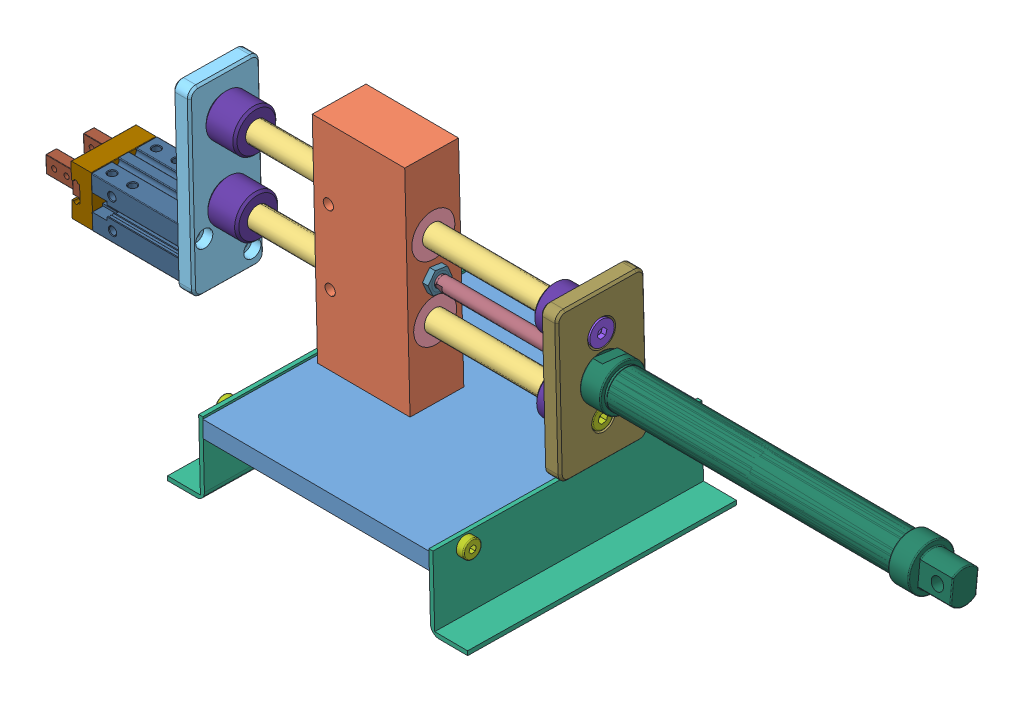
SolidWorks assembly cum s3, configuration Default. Lengths in mm.
Overall size (436.68 137.7 128.52).
36 component instances, 17 part files, 73 mates.
Components (placement in the parent):
- tam de lon-1: tam de lon [Default] at (119.0958 51.1975 54.0073) x (-0.999587 -0.017639 -0.022689) z (-0.022562 -0.007384 0.999718) size (110 8 125)
- con truot s1-2: con truot s1 [Default] at (88.5768 136.6703 53.9498) x (0.999587 0.017639 0.022689) z (0.022562 0.007384 -0.999718) size (45 102 25)
- chot dan huong-1: chot dan huong [Default] at (10.2966 117.7866 52.0436) x (0.021471 -0.983136 -0.181614) z (-0.019103 -0.182026 0.983108) size (10 175 10)
- chot dan huong-2: chot dan huong [Default] at (10.9197 82.793 51.7993) x (0.026236 -0.237789 -0.970963) z (0.011731 -0.971157 0.238153) size (10 175 10)
- bac lot-1: bac lot [Default] at (66.3976 118.7766 53.3171) x (0.028076 -0.767933 -0.639915) z (-0.006137 -0.640287 0.768111) size (20 12 20)
- bac lot-2: bac lot [Default] at (67.0207 83.783 53.0727) x (0.018145 -0.999587 -0.022287) z (-0.022287 -0.022689 0.999494) size (20 12 20)
- bac lot-3: bac lot [Default] at (111.379 119.5704 54.3381) x (-0.014484 -0.372719 0.927831) z (0.024823 -0.927776 -0.37231) size (20 12 20)
- bac lot-4: bac lot [Default] at (112.0021 84.5768 54.0937) x (-0.014484 -0.372719 0.927831) z (0.024823 -0.927776 -0.37231) size (20 12 20)
- ban canh truoc-1: ban canh truoc [Default] at (10.7506 92.2913 51.8656) x (-0.022562 -0.007384 0.999718) z (0.017801 -0.999817 -0.006983) size (33 8 86)
- khoi do-1: khoi do [Default] at (173.7917 36.5109 117.6508) x (0.022562 0.007384 -0.999718) z (-0.999587 -0.017639 -0.022689) size (125 35 18)
- khoi do-2: khoi do [Default] at (64.9414 35.4633 -9.8487) x (-0.022562 -0.007384 0.999718) z (0.999587 0.017639 0.022689) size (125 35 18)
- socket head thin cap screw_din-2: socket head thin cap screw_din [DIN 7984 - M5 x 12 --- 9.6N] at (57.6203 45.7804 100.0932) x (0.999587 0.017639 0.022689) z (-0.022689 -0.0002 0.999743) size (15.5 8.5 8.5)
- socket head thin cap screw_din-3: socket head thin cap screw_din [DIN 7984 - M5 x 12 --- 9.6N] at (59.7637 46.4818 5.12) x (0.999587 0.017639 0.022689) z (-0.022689 -0.0002 0.999743) size (15.5 8.5 8.5)
- socket head thin cap screw_din-4: socket head thin cap screw_din [DIN 7984 - M5 x 12 --- 9.6N] at (180.7137 48.6161 7.8654) x (-0.999587 -0.017639 -0.022689) z (0.022689 -0.968916 -0.246346) size (15.5 8.5 8.5)
- socket head thin cap screw_din-5: socket head thin cap screw_din [DIN 7984 - M5 x 12 --- 9.6N] at (178.5703 47.9147 102.8386) x (-0.999587 -0.017639 -0.022689) z (0.022689 -0.968916 -0.246346) size (15.5 8.5 8.5)
- socket head thin cap screw_din-6: socket head thin cap screw_din [DIN 7984 - M5 x 12 --- 9.6N] at (108.0343 45.1492 61.2151) x (-0.017801 0.999817 0.006983) z (-0.006983 -0.007108 0.99995) size (15.5 8.5 8.5)
- socket head thin cap screw_din-7: socket head thin cap screw_din [DIN 7984 - M5 x 12 --- 9.6N] at (72.3876 44.6249 45.4025) x (-0.017801 0.999817 0.006983) z (-0.006983 -0.007108 0.99995) size (15.5 8.5 8.5)
- socket head thin cap screw_din-10: socket head thin cap screw_din [DIN 7984 - M6 x 14 --- 11N] at (3.1229 82.6555 51.6223) x (0.999587 0.017639 0.022689) z (-0.022689 -0.0002 0.999743) size (18 10 10)
- socket csink head cap screw 10642_din-2: socket csink head cap screw 10642_din [EN ISO 10642 - M6 x 16 - 16N] at (2.08 117.6417 51.8571) x (0.999587 0.017639 0.022689) z (-0.022678 -0.000819 0.999742) size (16 11.34 11.34)
- NMHZ2-16D-1: NMHZ2-16D [Default] at (18.7852 62.0278 29.4102) x (-0.022562 -0.007384 0.999718) z (-0.999587 -0.017639 -0.022689) size (30.6 23.6 52.5)
  - NMHZ2-16D Slipway-1: NMHZ2-16D Slipway [Default] at (22.4069 2.6078 57.488) size (30.1 23.6 10)
  - NMHZ2-16D cylinder-2: NMHZ2-16D cylinder [Default] at (22.4069 2.6078 14.988) size (30.6 23.6 42.5)
- NMHZ2-16D air claw-1: NMHZ2-16D air claw [Default] at (-47.2443 63.3091 51.0796) x (-0.022562 -0.007384 0.999718) z (-0.999587 -0.017639 -0.022689) size (12 10 21)
- NMHZ2-16D air claw-2: NMHZ2-16D air claw [Default] at (-47.1889 63.3273 48.6222) x (0.022562 0.007384 -0.999718) z (-0.999587 -0.017639 -0.022689) size (12 10 21)
- ban canh sau-1: ban canh sau [Default] at (185.5359 103.3766 55.8921) x (-0.022562 -0.007384 0.999718) z (-0.017801 0.999817 0.006983) size (41 8 70)
- socket head thin cap screw_din-11: socket head thin cap screw_din [DIN 7984 - M6 x 14 --- 11N] at (193.6442 86.0174 55.9469) x (-0.999587 -0.017639 -0.022689) z (0.022689 -0.968916 -0.246346) size (18 10 10)
- socket csink head cap screw 10642_din-6: socket csink head cap screw 10642_din [EN ISO 10642 - M6 x 16 - 16N] at (193.441 121.0184 56.2008) x (-0.999587 -0.017639 -0.022689) z (0.022777 -0.96767 -0.251187) size (16 11.34 11.34)
- Part1-1: Part1 [Default] at (260.6534 104.7022 57.5972) x (-0.014484 -0.372719 0.927831) z (0.024823 -0.927776 -0.37231) size (6.2 165 6.2)
- Part2-1: Part2 [Default] at (113.19 102.1 54.2499) x (0.000299 -0.795842 0.605505) z (0.028738 -0.605248 -0.795518) size (11.32 3 9.8)
- Assem2-1: Assem2 [Default] at (390.8157 29.8557 191.0632) x (0.024605 -0.1173 -0.992792) z (0.999587 0.017639 0.022689) size (21.5 21.5 192)
  - 16 X 100 Cylinder bore-1: 16 X 100 Cylinder bore [Default] at (120.5218 91.9581 -118.7652) size (21.5 21.5 192)
- prevailing torque nut style 2 fine_din-3: prevailing torque nut style 2 fine_din [DIN EN ISO 10513 - M10x1 - N] at (175.54 103.2002 55.6652) x (-0.025491 0.908776 0.416506) z (-0.999587 -0.017639 -0.022689) size (17.25 18.48 10)
- bac chan-1: bac chan [Default] at (10.2966 117.7866 52.0436) x (0.014063 0.388293 -0.921429) z (0.025063 -0.921367 -0.387885) size (20 15 20)
- bac chan-2: bac chan [Default] at (10.9197 82.793 51.7993) x (0.014063 0.388293 -0.921429) z (0.025063 -0.921367 -0.387885) size (20 15 20)
- bac chan-3: bac chan [Default] at (170.2305 120.6089 55.6739) x (0.016197 -0.997929 0.062249) z (-0.02374 0.061856 0.997803) size (20 15 20)
- bac chan-4: bac chan [Default] at (170.8536 85.6153 55.4295) x (0.016861 -0.999279 0.034017) z (-0.023273 0.03362 0.999164) size (20 15 20)
Mates (geometry in assembly coordinates):
- Parallel5: parallel anti-aligned: plane of tam de lon-1 through (119.0958 51.1975 54.0073) normal (-0.017801 0.999817 0.006983); plane of con truot s1-2 through (90.1077 50.686 53.3493) normal (0.017801 -0.999817 -0.006983)
- Parallel6: parallel anti-aligned: plane of tam de lon-1 through (172.8053 43.7076 117.6817) normal (-0.022562 -0.007384 0.999718); plane of con truot s1-2 through (67.6142 66.3785 40.454) normal (0.022562 0.007384 -0.999718)
- Concentric3: concentric aligned: cylinder of tam de lon-1 through (72.2844 50.4239 45.443) axis (0.017801 -0.999817 -0.006983) radius 2.75; circle of con truot s1-2
- Coincident1: coincident anti-aligned: plane of tam de lon-1 through (119.0958 51.1975 54.0073) normal (-0.017801 0.999817 0.006983); plane of con truot s1-2 through (90.1077 50.686 53.3493) normal (0.017801 -0.999817 -0.006983)
- Concentric4: concentric anti-aligned: cylinder of con truot s1-2 through (41.408 118.3356 52.7498) axis (0.999587 0.017639 0.022689) radius 6; cylinder of chot dan huong-1 through (283.1839 122.602 58.2378) axis (-0.999587 -0.017639 -0.022689) radius 5
- Concentric5: concentric anti-aligned: cylinder of con truot s1-2 through (42.031 83.342 52.5054) axis (0.999587 0.017639 0.022689) radius 6; cylinder of chot dan huong-2 through (283.8069 87.6084 57.9934) axis (-0.999587 -0.017639 -0.022689) radius 5
- Concentric6: concentric anti-aligned: cylinder of con truot s1-2 through (41.408 118.3356 52.7498) axis (0.999587 0.017639 0.022689) radius 6; cylinder of bac lot-1 through (78.3927 118.9883 53.5893) axis (-0.999587 -0.017639 -0.022689) radius 6
- Coincident2: coincident anti-aligned: plane of con truot s1-2 through (68.3968 118.8119 53.3624) normal (-0.999587 -0.017639 -0.022689); plane of bac lot-1 through (68.3968 118.8119 53.3624) normal (0.999587 0.017639 0.022689)
- Concentric7: concentric anti-aligned: cylinder of con truot s1-2 through (42.031 83.342 52.5054) axis (0.999587 0.017639 0.022689) radius 6; cylinder of bac lot-2 through (79.0157 83.9947 53.3449) axis (-0.999587 -0.017639 -0.022689) radius 6
- Coincident3: coincident anti-aligned: plane of con truot s1-2 through (69.0199 83.8183 53.1181) normal (-0.999587 -0.017639 -0.022689); plane of bac lot-2 through (69.0199 83.8183 53.1181) normal (0.999587 0.017639 0.022689)
- Concentric8: concentric aligned: cylinder of con truot s1-2 through (41.408 118.3356 52.7498) axis (0.999587 0.017639 0.022689) radius 6; cylinder of bac lot-3 through (99.384 119.3587 54.0658) axis (0.999587 0.017639 0.022689) radius 6
- Coincident4: coincident anti-aligned: plane of con truot s1-2 through (109.3799 119.5351 54.2927) normal (0.999587 0.017639 0.022689); plane of bac lot-3 through (109.3799 119.5351 54.2927) normal (-0.999587 -0.017639 -0.022689)
- Concentric9: concentric aligned: cylinder of con truot s1-2 through (42.031 83.342 52.5054) axis (0.999587 0.017639 0.022689) radius 6; cylinder of bac lot-4 through (100.0071 84.3651 53.8214) axis (0.999587 0.017639 0.022689) radius 6
- Coincident5: coincident anti-aligned: plane of con truot s1-2 through (110.0029 84.5415 54.0483) normal (0.999587 0.017639 0.022689); plane of bac lot-4 through (110.0029 84.5415 54.0483) normal (-0.999587 -0.017639 -0.022689)
- Concentric10: concentric aligned: cylinder of chot dan huong-1 through (283.1839 122.602 58.2378) axis (-0.999587 -0.017639 -0.022689) radius 5; cylinder of ban canh truoc-1 through (10.2966 117.7866 52.0436) axis (-0.999587 -0.017639 -0.022689) radius 3.3
- Concentric11: concentric aligned: cylinder of chot dan huong-2 through (283.8069 87.6084 57.9934) axis (-0.999587 -0.017639 -0.022689) radius 5; cylinder of ban canh truoc-1 through (10.9197 82.793 51.7993) axis (-0.999587 -0.017639 -0.022689) radius 3.3
- Coincident6: coincident anti-aligned: plane of chot dan huong-1 through (10.2966 117.7866 52.0436) normal (-0.999587 -0.017639 -0.022689); plane of ban canh truoc-1 through (10.7506 92.2913 51.8656) normal (0.999587 0.017639 0.022689)
- Coincident7: coincident anti-aligned: plane of chot dan huong-2 through (10.9197 82.793 51.7993) normal (-0.999587 -0.017639 -0.022689); plane of ban canh truoc-1 through (10.7506 92.2913 51.8656) normal (0.999587 0.017639 0.022689)
- Parallel7: parallel aligned: plane of tam de lon-1 through (65.671 42.6903 -9.7789) normal (-0.999587 -0.017639 -0.022689); plane of khoi do-1 through (176.0884 18.6354 -7.4646) normal (-0.999587 -0.017639 -0.022689)
- Parallel8: parallel aligned: plane of tam de lon-1 through (119.0958 51.1975 54.0073) normal (-0.017801 0.999817 0.006983); plane of khoi do-1 through (175.4654 53.629 -7.2202) normal (-0.017801 0.999817 0.006983)
- Concentric14: concentric aligned: cylinder of tam de lon-1 through (160.2221 48.2545 7.4003) axis (0.999587 0.017639 0.022689) radius 2.5; cylinder of khoi do-1 through (52.2667 46.3495 4.9498) axis (0.999587 0.017639 0.022689) radius 2.5
- Coincident10: coincident anti-aligned: plane of tam de lon-1 through (175.6256 44.6306 -7.2831) normal (0.999587 0.017639 0.022689); plane of khoi do-1 through (176.0884 18.6354 -7.4646) normal (-0.999587 -0.017639 -0.022689)
- Parallel9: parallel anti-aligned: plane of tam de lon-1 through (65.671 42.6903 -9.7789) normal (-0.999587 -0.017639 -0.022689); plane of khoi do-2 through (63.3136 15.7721 115.0043) normal (0.999587 0.017639 0.022689)
- Parallel10: parallel anti-aligned: plane of tam de lon-1 through (119.0958 51.1975 54.0073) normal (-0.017801 0.999817 0.006983); plane of khoi do-2 through (63.3136 15.7721 115.0043) normal (0.017801 -0.999817 -0.006983)
- Concentric15: concentric aligned: cylinder of tam de lon-1 through (80.2552 46.8434 5.5851) axis (-0.999587 -0.017639 -0.022689) radius 2.5; cylinder of khoi do-2 through (188.2106 48.7484 8.0356) axis (-0.999587 -0.017639 -0.022689) radius 2.5
- Coincident11: coincident anti-aligned: plane of tam de lon-1 through (65.671 42.6903 -9.7789) normal (-0.999587 -0.017639 -0.022689); plane of khoi do-2 through (63.3136 15.7721 115.0043) normal (0.999587 0.017639 0.022689)
- Concentric16: concentric aligned: cylinder of khoi do-2 through (186.0672 48.047 103.0088) axis (-0.999587 -0.017639 -0.022689) radius 2.5; cylinder of socket head thin cap screw_din-2 through (25.8834 45.2204 99.3728) axis (-0.999587 -0.017639 -0.022689) radius 4.25
- Coincident12: coincident anti-aligned: plane of khoi do-2 through (61.2788 17.7365 114.9729) normal (-0.999587 -0.017639 -0.022689); plane of socket head thin cap screw_din-2 through (61.0438 50.0915 100.1718) normal (0.999587 0.017639 0.022689)
- Concentric17: concentric aligned: cylinder of khoi do-2 through (188.2106 48.7484 8.0356) axis (-0.999587 -0.017639 -0.022689) radius 2.5; cylinder of socket head thin cap screw_din-3 through (28.0268 45.9218 4.3996) axis (-0.999587 -0.017639 -0.022689) radius 4.25
- Coincident13: coincident anti-aligned: plane of khoi do-2 through (61.2788 17.7365 114.9729) normal (-0.999587 -0.017639 -0.022689); plane of socket head thin cap screw_din-3 through (63.1872 50.7929 5.1986) normal (0.999587 0.017639 0.022689)
- Concentric18: concentric aligned: cylinder of khoi do-1 through (52.2667 46.3495 4.9498) axis (0.999587 0.017639 0.022689) radius 2.5; cylinder of socket head thin cap screw_din-4 through (212.4506 49.1762 8.5858) axis (0.999587 0.017639 0.022689) radius 4.25
- Coincident14: coincident anti-aligned: plane of khoi do-1 through (178.052 20.6703 -7.4053) normal (0.999587 0.017639 0.022689); plane of socket head thin cap screw_din-4 through (177.2901 49.6031 3.6681) normal (-0.999587 -0.017639 -0.022689)
- Concentric19: concentric aligned: cylinder of khoi do-1 through (50.1234 45.6481 99.9231) axis (0.999587 0.017639 0.022689) radius 2.5; cylinder of socket head thin cap screw_din-5 through (210.3072 48.4747 103.559) axis (0.999587 0.017639 0.022689) radius 4.25
- Coincident15: coincident anti-aligned: plane of khoi do-1 through (178.052 20.6703 -7.4053) normal (0.999587 0.017639 0.022689); plane of socket head thin cap screw_din-5 through (175.1467 48.9017 98.6413) normal (-0.999587 -0.017639 -0.022689)
- Concentric20: concentric aligned: cylinder of tam de lon-1 through (107.972 48.6485 61.2395) axis (0.017801 -0.999817 -0.006983) radius 5; cylinder of socket head thin cap screw_din-6 through (108.5995 13.405 60.9934) axis (0.017801 -0.999817 -0.006983) radius 4.25
- Coincident16: coincident anti-aligned: plane of tam de lon-1 through (107.972 48.6485 61.2395) normal (0.017801 -0.999817 -0.006983); plane of socket head thin cap screw_din-6 through (103.7228 48.5731 61.2093) normal (-0.017801 0.999817 0.006983)
- Concentric21: concentric aligned: cylinder of tam de lon-1 through (72.2844 50.4239 45.443) axis (0.017801 -0.999817 -0.006983) radius 2.75; cylinder of socket head thin cap screw_din-7 through (72.9528 12.8807 45.1808) axis (0.017801 -0.999817 -0.006983) radius 4.25
- Coincident17: coincident anti-aligned: plane of tam de lon-1 through (72.3253 48.1243 45.4269) normal (0.017801 -0.999817 -0.006983); plane of socket head thin cap screw_din-7 through (68.0761 48.0489 45.3967) normal (-0.017801 0.999817 0.006983)
- Concentric23: concentric aligned: cylinder of ban canh truoc-1 through (7.1212 82.726 51.713) axis (-0.999587 -0.017639 -0.022689) radius 5.5; cylinder of socket head thin cap screw_din-10 through (-28.614 82.0954 50.9019) axis (-0.999587 -0.017639 -0.022689) radius 5
- Coincident19: coincident anti-aligned: plane of ban canh truoc-1 through (7.1212 82.726 51.713) normal (-0.999587 -0.017639 -0.022689); plane of socket head thin cap screw_din-10 through (7.0331 87.7252 51.712) normal (0.999587 0.017639 0.022689)
- Coincident20: coincident aligned: cone of ban canh truoc-1 through (5.4986 117.702 51.9347) axis (0.999587 0.017639 0.022689); cone of socket csink head cap screw 10642_din-2 through (3.1296 117.6602 51.881) axis (0.999587 0.017639 0.022689)
- Concentric24: concentric anti-aligned: cylinder of ban canh truoc-1 through (10.8638 71.9138 62.7207) axis (-0.999587 -0.017639 -0.022689) radius 2.25; cylinder of NMHZ2-16D-1/NMHZ2-16D cylinder-2 through (-12.1267 71.5081 62.1989) axis (0.999587 0.017639 0.022689) radius 2
- Concentric25: concentric aligned: cylinder of ban canh truoc-1 through (7.229 57.0014 40.5224) axis (0.999587 0.017639 0.022689) radius 4; cylinder of NMHZ2-16D-1/NMHZ2-16D cylinder-2 through (-11.3634 56.6733 40.1003) axis (0.999587 0.017639 0.022689) radius 2
- Coincident22: coincident anti-aligned: plane of ban canh truoc-1 through (2.7539 92.1502 51.6841) normal (-0.999587 -0.017639 -0.022689); plane of NMHZ2-16D-1/NMHZ2-16D cylinder-2 through (3.2514 64.2053 51.4889) normal (0.999587 0.017639 0.022689)
- Parallel11: parallel anti-aligned: plane of NMHZ2-16D-1/NMHZ2-16D Slipway-1 through (-44.7209 63.516 27.8948) normal (-0.999587 -0.017639 -0.022689); plane of NMHZ2-16D air claw-1 through (-45.5159 63.2558 63.1216) normal (0.999587 0.017639 0.022689)
- Concentric26: concentric anti-aligned: cylinder of NMHZ2-16D-1/NMHZ2-16D Slipway-1 through (-46.7913 67.4799 27.8774) axis (-0.022562 -0.007384 0.999718) radius 1; cylinder of NMHZ2-16D air claw-1 through (-47.5863 67.2198 63.1042) axis (0.022562 0.007384 -0.999718) radius 1
- Parallel12: parallel anti-aligned: plane of NMHZ2-16D-1/NMHZ2-16D Slipway-1 through (-44.7209 63.516 27.8948) normal (-0.999587 -0.017639 -0.022689); plane of NMHZ2-16D air claw-2 through (-44.919 63.4511 36.671) normal (0.999587 0.017639 0.022689)
- Concentric27: concentric aligned: cylinder of NMHZ2-16D-1/NMHZ2-16D Slipway-1 through (-46.6489 59.4814 27.8215) axis (-0.022562 -0.007384 0.999718) radius 1; cylinder of NMHZ2-16D air claw-2 through (-46.8469 59.4166 36.5977) axis (-0.022562 -0.007384 0.999718) radius 1
- Concentric28: concentric anti-aligned: cylinder of chot dan huong-1 through (283.1839 122.602 58.2378) axis (-0.999587 -0.017639 -0.022689) radius 5; cylinder of ban canh sau-1 through (185.2243 120.8734 56.0143) axis (0.999587 0.017639 0.022689) radius 3.3
- Concentric29: concentric anti-aligned: cylinder of chot dan huong-2 through (283.8069 87.6084 57.9934) axis (-0.999587 -0.017639 -0.022689) radius 5; cylinder of ban canh sau-1 through (185.8474 85.8798 55.7699) axis (0.999587 0.017639 0.022689) radius 3.3
- Coincident23: coincident anti-aligned: plane of chot dan huong-1 through (185.2243 120.8734 56.0143) normal (0.999587 0.017639 0.022689); plane of ban canh sau-1 through (185.5359 103.3766 55.8921) normal (-0.999587 -0.017639 -0.022689)
- Coincident24: coincident anti-aligned: plane of chot dan huong-2 through (185.8474 85.8798 55.7699) normal (0.999587 0.017639 0.022689); plane of ban canh sau-1 through (185.5359 103.3766 55.8921) normal (-0.999587 -0.017639 -0.022689)
- Concentric301: concentric aligned: cylinder of ban canh sau-1 through (185.8474 85.8798 55.7699) axis (0.999587 0.017639 0.022689) radius 3.3; cylinder of socket head thin cap screw_din-11 through (225.3811 86.5774 56.6673) axis (0.999587 0.017639 0.022689) radius 5
- Coincident251: coincident anti-aligned: plane of ban canh sau-1 through (189.6458 85.9469 55.8561) normal (0.999587 0.017639 0.022689); plane of socket head thin cap screw_din-11 through (189.734 87.1807 51.0115) normal (-0.999587 -0.017639 -0.022689)
- Coincident26: coincident aligned: cone of ban canh sau-1 through (190.0224 120.9581 56.1232) axis (-0.999587 -0.017639 -0.022689); cone of socket csink head cap screw 10642_din-6 through (192.3914 120.9999 56.177) axis (-0.999587 -0.017639 -0.022689)
- Concentric32: concentric aligned: cylinder of Part1-1 through (114.7137 102.1269 54.2845) axis (0.999587 0.017639 0.022689) radius 2.6; cylinder of Part2-1 through (114.6893 102.1265 54.284) axis (0.999587 0.017639 0.022689) radius 2.75
- Concentric33: concentric aligned: cylinder of con truot s1-2 through (96.6968 101.809 53.8756) axis (0.999587 0.017639 0.022689) radius 2.5; cylinder of Part1-1 through (114.7137 102.1269 54.2845) axis (0.999587 0.017639 0.022689) radius 2.6
- Lock1: lock: unknown of Part1-1; unknown of Part2-1
- Coincident27: coincident anti-aligned: plane of con truot s1-2 through (112.0316 66.9877 66.468) normal (0.999587 0.017639 0.022689); plane of Part2-1 through (111.6906 102.0736 54.2159) normal (-0.999587 -0.017639 -0.022689)
- Concentric34: concentric anti-aligned: cylinder of Part1-1 through (95.7216 101.7918 53.8534) axis (0.999587 0.017639 0.022689) radius 3.1; cylinder of Assem2-1/16 X 100 Cylinder bore-1 through (352.6668 106.3258 59.6857) axis (-0.999587 -0.017639 -0.022689) radius 3.25
- LimitDistance1: limit distance = 83.0514 mm anti-aligned: plane of Part1-1 through (260.6534 104.7022 57.5972) normal (0.999587 0.017639 0.022689); plane of Assem2-1/16 X 100 Cylinder bore-1 through (343.6705 106.1671 59.4815) normal (-0.999587 -0.017639 -0.022689)
- Coincident28: coincident anti-aligned: plane of ban canh sau-1 through (189.5342 103.4472 55.9828) normal (0.999587 0.017639 0.022689); plane of Assem2-1/16 X 100 Cylinder bore-1 through (189.5342 103.4472 55.9828) normal (-0.999587 -0.017639 -0.022689)
- Concentric36: concentric anti-aligned: cylinder of ban canh sau-1 through (183.5367 103.3414 55.8467) axis (0.999587 0.017639 0.022689) radius 5.1; cylinder of prevailing torque nut style 2 fine_din-3 through (200.5672 103.6419 56.2333) axis (-0.999587 -0.017639 -0.022689) radius 5
- Coincident30: coincident anti-aligned: plane of ban canh sau-1 through (185.5359 103.3766 55.8921) normal (-0.999587 -0.017639 -0.022689); plane of prevailing torque nut style 2 fine_din-3 through (185.6585 107.2279 47.4965) normal (0.999587 0.017639 0.022689)
- Concentric37: concentric anti-aligned: cylinder of chot dan huong-1 through (283.1839 122.602 58.2378) axis (-0.999587 -0.017639 -0.022689) radius 5; cylinder of bac chan-1 through (10.2966 117.7866 52.0436) axis (0.999587 0.017639 0.022689) radius 5
- Coincident31: coincident anti-aligned: plane of ban canh truoc-1 through (10.7506 92.2913 51.8656) normal (0.999587 0.017639 0.022689); plane of bac chan-1 through (10.2966 117.7866 52.0436) normal (-0.999587 -0.017639 -0.022689)
- Concentric38: concentric anti-aligned: cylinder of chot dan huong-2 through (283.8069 87.6084 57.9934) axis (-0.999587 -0.017639 -0.022689) radius 5; cylinder of bac chan-2 through (10.9197 82.793 51.7993) axis (0.999587 0.017639 0.022689) radius 5
- Coincident32: coincident anti-aligned: plane of ban canh truoc-1 through (10.7506 92.2913 51.8656) normal (0.999587 0.017639 0.022689); plane of bac chan-2 through (10.9197 82.793 51.7993) normal (-0.999587 -0.017639 -0.022689)
- Concentric391: concentric aligned: cylinder of chot dan huong-1 through (283.1839 122.602 58.2378) axis (-0.999587 -0.017639 -0.022689) radius 5; cylinder of bac chan-3 through (185.2243 120.8734 56.0143) axis (-0.999587 -0.017639 -0.022689) radius 10
- Coincident33: coincident anti-aligned: plane of ban canh sau-1 through (185.5359 103.3766 55.8921) normal (-0.999587 -0.017639 -0.022689); plane of bac chan-3 through (185.2243 120.8734 56.0143) normal (0.999587 0.017639 0.022689)
- Concentric401: concentric aligned: cylinder of chot dan huong-2 through (283.8069 87.6084 57.9934) axis (-0.999587 -0.017639 -0.022689) radius 5; cylinder of bac chan-4 through (185.8474 85.8798 55.7699) axis (-0.999587 -0.017639 -0.022689) radius 10
- Coincident34: coincident anti-aligned: plane of ban canh sau-1 through (185.5359 103.3766 55.8921) normal (-0.999587 -0.017639 -0.022689); plane of bac chan-4 through (185.8474 85.8798 55.7699) normal (0.999587 0.017639 0.022689)
- LimitDistance2: limit distance = 41.1242 mm anti-aligned: plane of bac chan-1 through (25.2904 118.0512 52.384) normal (0.999587 0.017639 0.022689); plane of con truot s1-2 through (67.0502 66.1939 65.447) normal (-0.999587 -0.017639 -0.022689)
